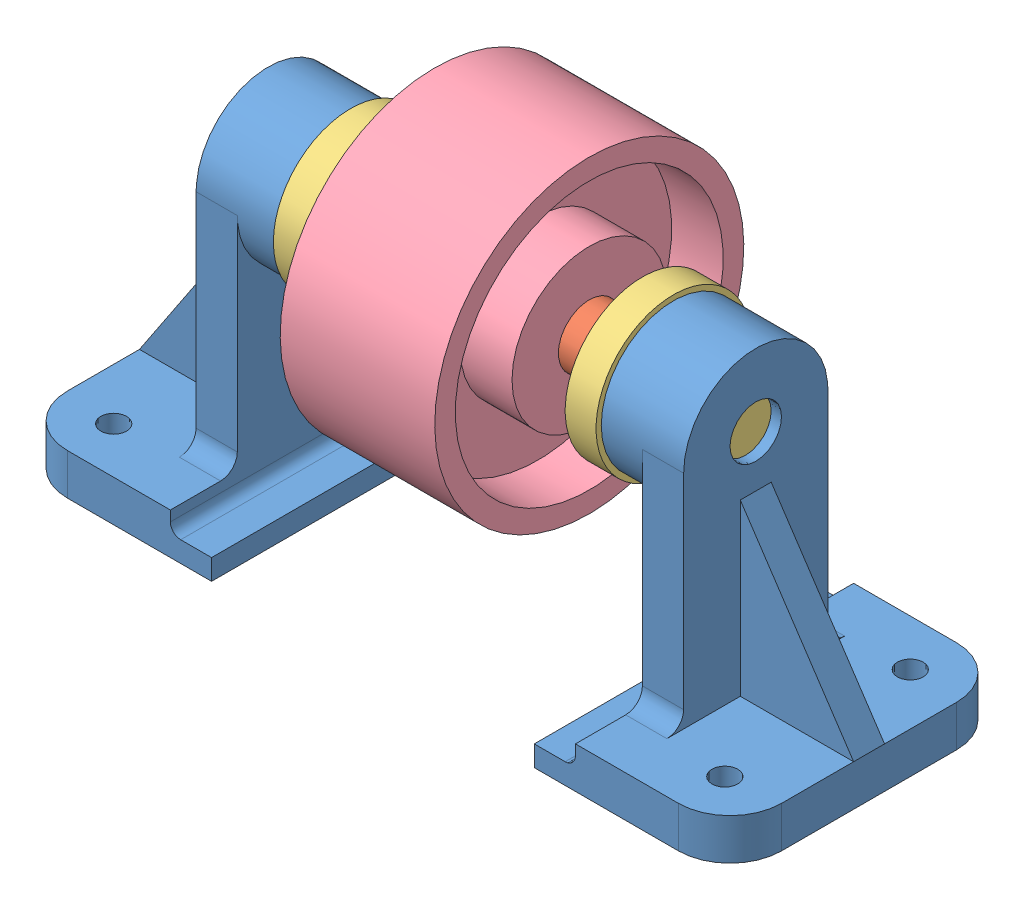
SolidWorks assembly Montaj1, configuration Varsayılan. Lengths in mm.
Overall size (138.64 91.32 80.64).
6 component instances, 4 part files, 12 mates.
Components (placement in the parent):
- Parça2-1: Parça2 [Varsayılan] at (-26.6297 -24.8488 65) size (38 65 54)
- Parça2-2: Parça2 [Varsayılan] at (74.0108 -24.8488 65) x (-1 0 0) z (0 0 -1) size (38 65 54)
- Parça5-1: Parça5 [Varsayılan] at (-1.3094 26.1512 65) x (1 0 0) z (0 -0.922648 0.385642) size (82 12 12)
- Parça3-2: Parça3 [Varsayılan] at (-7.6297 26.1512 65) size (20 30 30)
- Parça3-3: Parça3 [Varsayılan] at (55.0108 26.1512 65) x (-1 0 0) z (0 0 -1) size (20 30 30)
- Parça4-2: Parça4 [Varsayılan] at (8.6906 26.1512 65) x (1 0 0) z (0 0.892081 -0.451875) size (30 60 60)
Mates (geometry in assembly coordinates):
- Paralel1: parallel: plane of Parça2-1 through (-7.6297 -16.8488 38) normal (1 0 0); plane of Parça2-2 through (55.0108 -16.8488 92) normal (-1 0 0)
- Eş Merkezli3: concentric: cylinder of Parça2-1 through (-23.6297 26.1512 65) axis (1 0 0) radius 5; cylinder of Parça3-2 through (-21.6297 26.1512 65) axis (1 0 0) radius 5
- Çakışık3: coincident: plane of Parça2-1 through (-7.6297 26.1512 65) normal (1 0 0); plane of Parça3-2 through (-7.6297 26.1512 65) normal (-1 0 0)
- Eş Merkezli4: concentric: cylinder of Parça2-2 through (71.0108 26.1512 65) axis (-1 0 0) radius 5; cylinder of Parça3-3 through (69.0108 26.1512 65) axis (-1 0 0) radius 5
- Çakışık4: coincident: plane of Parça2-2 through (55.0108 26.1512 65) normal (-1 0 0); plane of Parça3-3 through (55.0108 26.1512 65) normal (1 0 0)
- Paralel2: parallel: plane of Parça2-1 through (-35.6297 -24.8488 48) normal (0 -1 0); plane of Parça2-2 through (83.0108 -24.8488 82) normal (0 -1 0)
- Eş Merkezli6: concentric: circle of Parça3-2; circle of Parça3-3
- Eş Merkezli7: concentric: cylinder of Parça5-1 through (-17.3094 26.1512 65) axis (1 0 0) radius 5; cylinder of Parça3-2 through (-24.6003 26.1512 65) axis (1 0 0) radius 5
- Eş Merkezli8: concentric: cylinder of Parça5-1 through (64.6906 26.1512 65) axis (-1 0 0) radius 5; cylinder of Parça3-3 through (71.9814 26.1512 65) axis (-1 0 0) radius 5
- Genişlik1: width: plane of Parça3-2 through (-1.6297 26.1512 65) normal (1 0 0); plane of Parça3-3 through (49.0108 26.1512 65) normal (-1 0 0); plane of Parça5-1 through (48.6906 26.1512 65) normal (1 0 0); plane of Parça5-1 through (-1.3094 26.1512 65) normal (-1 0 0)
- Kilitle1: lock: unknown of Parça3-2; unknown of Parça3-3
- Eş Merkezli10: concentric: cylinder of Parça5-1 through (48.6906 26.1512 65) axis (-1 0 0) radius 6; cylinder of Parça4-2 through (66.9748 26.1512 65) axis (-1 0 0) radius 6
